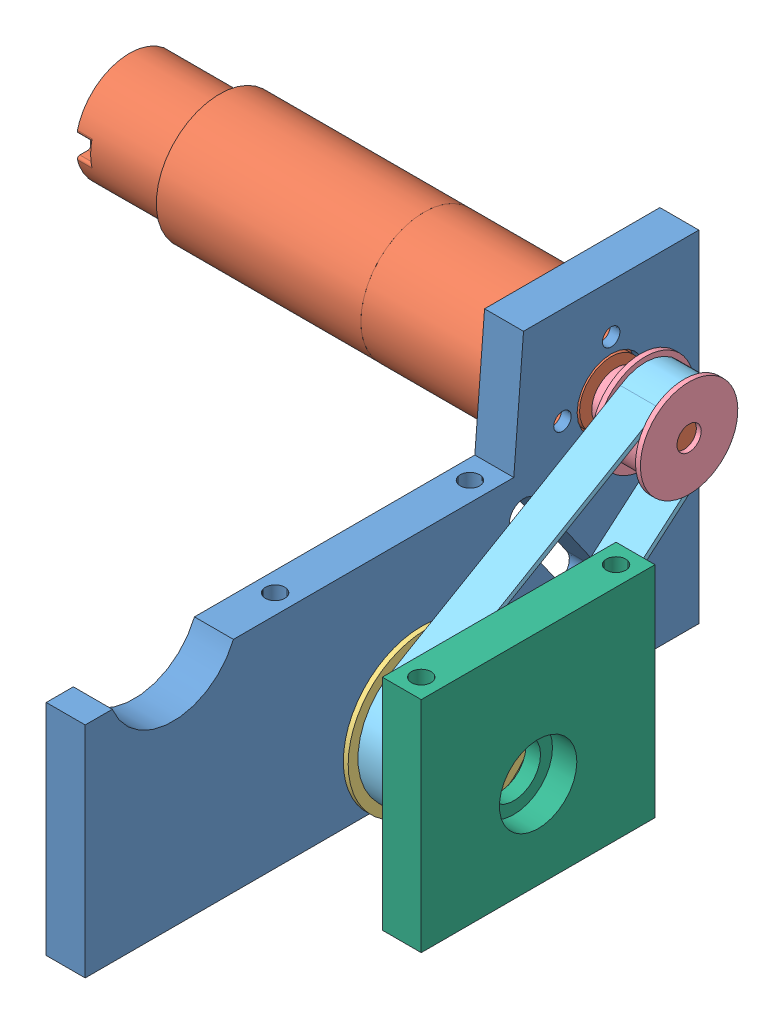
SolidWorks assembly Assemblage Moteur BRS, configuration Défaut. Lengths in mm.
Overall size (128.9 70 126).
6 component instances, 6 part files, 7 mates.
Components (placement in the parent):
- Support Moteur BRS-1: Support Moteur BRS [Défaut] at (-7.2218 -30.0825 126) size (8 70 126)
- Moteur faulhaber D26 BRS Access-1: Moteur faulhaber D26 BRS Access [Défaut] at (-37.6218 19.9175 49) x (0 0 -1) z (1 0 0) size (26 26 113.9)
- Poulie D32 BRS-1: Poulie D32 BRS [Défaut] at (16.7782 -12.0825 94) x (0 0 1) z (-1 0 0) size (32 32 15.5)
- Poulie D20 BRS-1: Poulie D20 BRS [Défaut] at (16.7782 19.9175 49) x (0 0.974536 0.224231) z (-1 0 0) size (20 20 15)
- Courroie tendu BRS-1: Courroie tendu BRS [Défaut] at (15.7782 -12.0825 94) x (0 0 1) z (-1 0 0) size (68 55 8)
- Support Axe Roue BRS-1: Support Axe Roue BRS [Défaut] at (22.7782 -30.0825 118) size (8 45 48)
Mates (geometry in assembly coordinates):
- Coaxiale1: concentric aligned: cylinder of Support Moteur BRS-1 through (-1.2218 19.9175 49) axis (-1 0 0) radius 13.4; cylinder of Moteur faulhaber D26 BRS Access-1 through (-1.2218 19.9175 49) axis (-1 0 0) radius 13
- Coaxiale2: concentric anti-aligned: cylinder of Support Moteur BRS-1 through (2.7782 19.9175 59) axis (-1 0 0) radius 1.8; cylinder of Moteur faulhaber D26 BRS Access-1 through (-5.2218 19.9175 59) axis (1 0 0) radius 1.8
- Coïncidente1: coincident anti-aligned: plane of Support Moteur BRS-1 through (-1.2218 19.9175 49) normal (-1 0 0); plane of Moteur faulhaber D26 BRS Access-1 through (-1.2218 19.9175 49) normal (1 0 0)
- Coaxiale3: concentric aligned: cylinder of Moteur faulhaber D26 BRS Access-1 through (15.7782 19.9175 49) axis (-1 0 0) radius 2.5; cylinder of Poulie D20 BRS-1 through (16.7782 19.9175 49) axis (-1 0 0) radius 2.5
- Coïncidente2: coincident anti-aligned: circle of Moteur faulhaber D26 BRS-1; plane of Poulie D20 BRS-1 through (1.7782 19.9175 49) normal (-1 0 0)
- Coïncidente3: coincident aligned: circle of Poulie D20 BRS-1; circle of Courroie tendu BRS-1
- Coïncidente4: coincident anti-aligned: circle of Poulie D32 BRS-1; circle of Courroie tendu BRS-1
